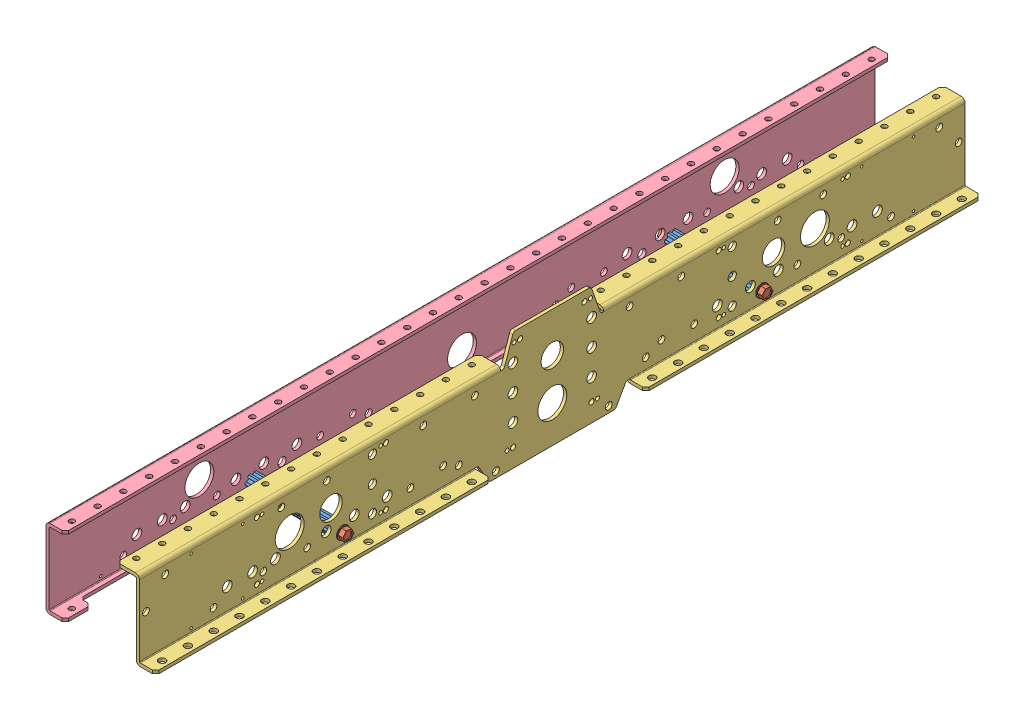
SolidWorks assembly AM14U3Long_Frame_Half, configuration Default. Lengths in mm.
Overall size (113.54 116.33 812.8).
8 component instances, 4 part files, 0 mates.
Components (placement in the parent):
- 500Churro_3.375-2: 500Churro_3.375 [Default] at (-501.65 -66.929 562.737) x (0 0 1) z (-1 0 0) size (14.66 12.7 85.72)
- 500Churro_3.375-4: 500Churro_3.375 [Default] at (-501.65 -66.929 149.987) x (0 0 1) z (-1 0 0) size (14.66 12.7 85.72)
- ThreadRollingScrew_0.25-20x0.75_FHTS 0.25-20-G-0.75-C-1: ThreadRollingScrew_0.25-20x0.75_FHTS 0.25-20-G-0.75-C [Default] at (-498.475 -66.929 562.737) x (-1 0 0) z (0 0.924225 0.381849) size (24.64 12.19 12.19)
- ThreadRollingScrew_0.25-20x0.75_FHTS 0.25-20-G-0.75-C-4: ThreadRollingScrew_0.25-20x0.75_FHTS 0.25-20-G-0.75-C [Default] at (-498.475 -66.929 149.987) x (-1 0 0) z (0 0.924225 0.381849) size (24.64 12.19 12.19)
- ThreadRollingScrew_0.25-20x0.75_FHTS 0.25-20-G-0.75-C-5: ThreadRollingScrew_0.25-20x0.75_FHTS 0.25-20-G-0.75-C [Default] at (-590.55 -66.929 562.737) size (24.64 12.19 12.19)
- ThreadRollingScrew_0.25-20x0.75_FHTS 0.25-20-G-0.75-C-7: ThreadRollingScrew_0.25-20x0.75_FHTS 0.25-20-G-0.75-C [Default] at (-590.55 -66.929 149.987) size (24.64 12.19 12.19)
- AM14U3InnerPlate_Long-1: AM14U3InnerPlate_Long [Default] at (-501.65 -77.216 762.762) x (0 0 -1) z (0 -1 0) size (812.8 38.1 116.33)
- AM14U3OuterPlate_Long_DefaultSM-FLAT-PATTERN-1: AM14U3OuterPlate_Long_DefaultSM-FLAT-PATTERN [Default] at (-587.375 -77.216 -50.038) x (0 0 1) z (0 -1 0) size (812.8 19.05 77.72)
